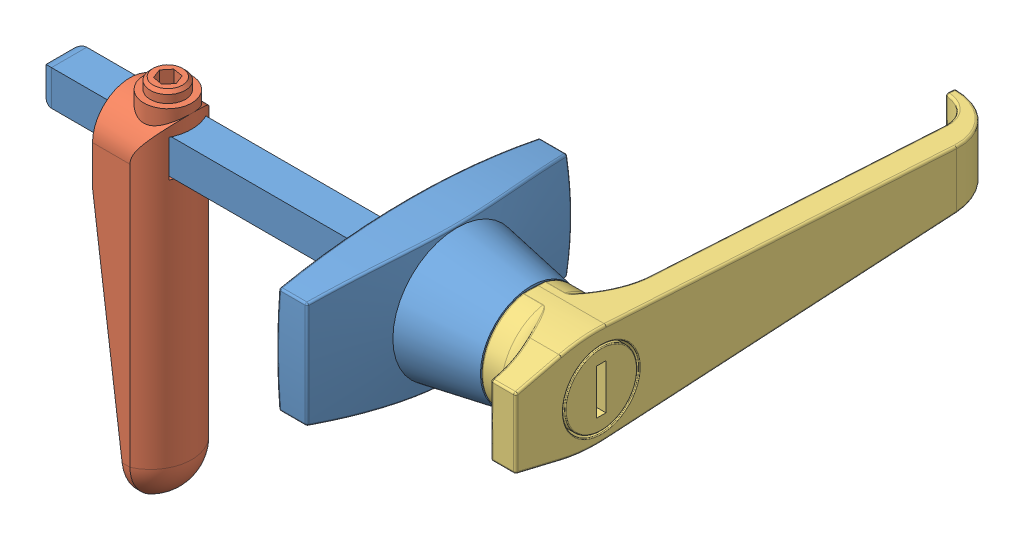
SolidWorks assembly Дверной замок (в сборе), configuration По умолчанию. Lengths in mm.
Overall size (123.64 88.45 122.71).
3 component instances, 3 part files, 5 mates.
Components (placement in the parent):
- Патрон-1: Патрон [По умолчанию] at (89.0346 64.6052 59.1377) size (107.77 32.94 60.58)
- Щеколда-1: Щеколда [По умолчанию] at (26.0346 63.2343 67.8389) size (14 80.97 17)
- Рукоять-2: Рукоять [По умолчанию] at (92.6793 64.6052 78.5168) size (15.88 38.16 111.8)
Mates (geometry in assembly coordinates):
- Совпадение2: coincident anti-aligned: plane of Патрон-1 through (9.0346 68.6052 55.1377) normal (0 1 0); plane of Щеколда-1 through (46.0346 68.6052 63.5377) normal (0 -1 0)
- Совпадение3: coincident anti-aligned: plane of Патрон-1 through (9.0346 68.6052 55.1377) normal (0 0 -1); plane of Щеколда-1 through (46.0346 60.2052 55.1377) normal (0 0 1)
- Расстояние1: distance = 63 mm aligned: plane of Щеколда-1 through (26.0346 63.2343 59.3377) normal (-1 0 0); plane of Патрон-1 through (89.0346 130.376 2.0127) normal (-1 0 0)
- Совпадение4: coincident anti-aligned: plane of Патрон-1 through (116.8039 64.6052 47.6048) normal (1 0 0); plane of Рукоять-2 through (116.8039 64.6052 59.1377) normal (-1 0 0)
- Концентричный1: concentric anti-aligned: circle of Патрон-1; circle of Рукоять-2
